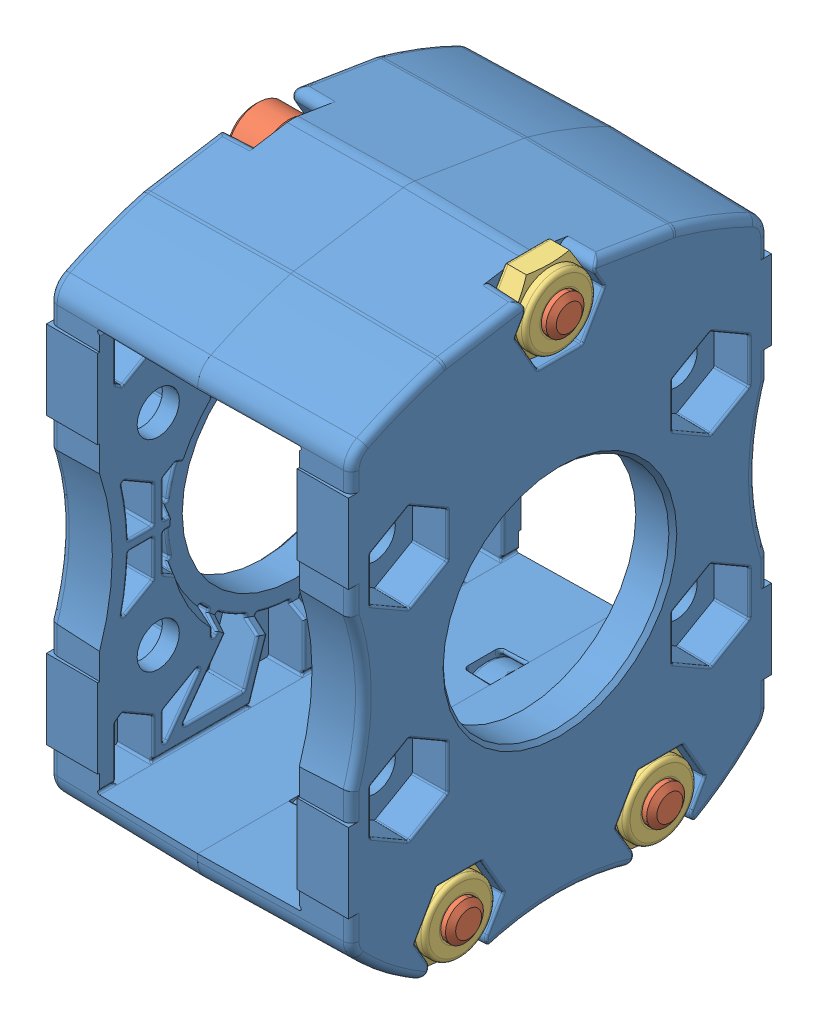
SolidWorks assembly 217-4155-STEP-20140806, configuration Default. Lengths in mm.
Overall size (39.75 73.98 53.68).
8 component instances, 3 part files, 0 mates.
Components (placement in the parent):
- 217-4155-001 Rev6-1: 217-4155-001 Rev6 [Default] at (0 0 714.7682) x (0 0 -1) z (1 0 0) size (53.68 71 22.06)
- 217-4155-001 Rev6-2: 217-4155-001 Rev6 [Default] at (0 0 714.7682) x (0 0 1) z (-1 0 0) size (53.68 71 22.06)
- 217-4155-003 Rev1_SSA1032-1375ZB-1: 217-4155-003 Rev1_SSA1032-1375ZB [Default] at (-14.7 29.95 714.7682) x (0 1 0) z (0 0 1) size (7.87 39.75 7.87)
- 217-4155-003 Rev1_SSA1032-1375ZB-2: 217-4155-003 Rev1_SSA1032-1375ZB [Default] at (-14.7 -29.95 702.0682) x (0 1 0) z (0 0 1) size (7.87 39.75 7.87)
- 217-4155-003 Rev1_SSA1032-1375ZB-3: 217-4155-003 Rev1_SSA1032-1375ZB [Default] at (-14.7 -29.95 727.4682) x (0 1 0) z (0 0 1) size (7.87 39.75 7.87)
- 217-4155-002 Rev2_NNY1032-ZC-1: 217-4155-002 Rev2_NNY1032-ZC [Default] at (14.7 29.95 714.7682) x (0 -0.5 -0.866025) z (1 0 0) size (9.39 10.84 4.45)
- 217-4155-002 Rev2_NNY1032-ZC-2: 217-4155-002 Rev2_NNY1032-ZC [Default] at (14.7 -29.95 702.0682) x (0 -0.5 -0.866025) z (1 0 0) size (9.39 10.84 4.45)
- 217-4155-002 Rev2_NNY1032-ZC-3: 217-4155-002 Rev2_NNY1032-ZC [Default] at (14.7 -29.95 727.4682) x (0 0.5 -0.866025) z (1 0 0) size (9.39 10.84 4.45)
